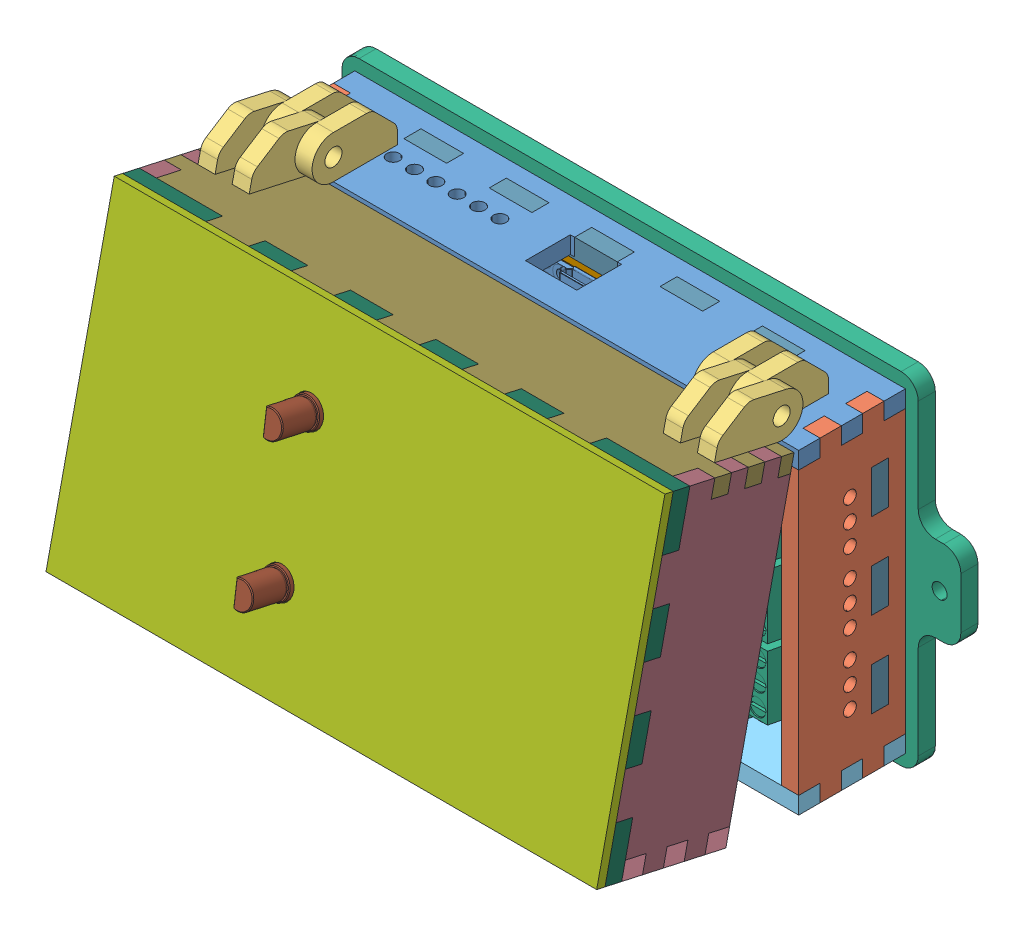
SolidWorks assembly KOOS, configuration Default. Lengths in mm.
Overall size (155 90.12 82.75).
54 component instances, 25 part files, 76 mates.
Components (placement in the parent):
- pcb^KOOS-1: pcb^KOOS [Default] at origin size (120 66.17 17.4) (virtual)
  - RaspberryPi_Pico_W^pcb_KOOS-1: RaspberryPi_Pico_W^pcb_KOOS [Default] at (102.465 -119.53 1.595) size (21 52.3 3.7) (virtual)
    - RaspberryPi_Pico_W_Module_KiCad^RaspberryPi_Pico_W_pcb_KOOS-1: RaspberryPi_Pico_W_Module_KiCad^RaspberryPi_Pico_W_pcb_KOOS [Default] at origin size (21 52.3 3.7) (virtual)
  - D_DO-41_SOD81_P10.16mm_Horizontal^pcb_KOOS-1: D_DO-41_SOD81_P10.16mm_Horizontal^pcb_KOOS [Default] at (136.74 -110.4 1.595) size (10.96 2.72 5.71) (virtual)
  - TerminalBlock_Phoenix_MKDS-1,5-2_1x02_P5.00mm_Horizontal^pcb_KOOS-1: TerminalBlock_Phoenix_MKDS-1,5-2_1x02_P5.00mm_Horizontal^pcb_KOOS [Default] at (49.6 -107.9 1.595) x (0 -1 0) z (0 0 1) size (10.74 9.8 17.3) (virtual)
  - R_Axial_DIN0207_L6.3mm_D2.5mm_P10.16mm_Horizontal^pcb_KOOS-1: R_Axial_DIN0207_L6.3mm_D2.5mm_P10.16mm_Horizontal^pcb_KOOS [Default] at (146.075 -143.595 1.595) x (0 1 0) z (0 0 1) size (10.76 2.5 5.5) (virtual)
  - DIP-4_W7.62mm^pcb_KOOS-1: DIP-4_W7.62mm^pcb_KOOS [Default] at (132.125 -128.705 1.595) x (0 1 0) z (0 0 1) size (7.87 4.93 6.98) (virtual)
  - TerminalBlock_Phoenix_MKDS-1,5-2_1x02_P5.00mm_Horizontal^pcb_KOOS-2: TerminalBlock_Phoenix_MKDS-1,5-2_1x02_P5.00mm_Horizontal^pcb_KOOS [Default] at (74.5 -151.5 1.595) size (10.74 9.8 17.3) (virtual)
  - TerminalBlock_Phoenix_MKDS-1,5-3_1x03_P5.00mm_Horizontal^pcb_KOOS-1: TerminalBlock_Phoenix_MKDS-1,5-3_1x03_P5.00mm_Horizontal^pcb_KOOS [Default] at (58 -151.5 1.595) size (15.74 9.8 17.3) (virtual)
  - R_Axial_DIN0207_L6.3mm_D2.5mm_P10.16mm_Horizontal^pcb_KOOS-2: R_Axial_DIN0207_L6.3mm_D2.5mm_P10.16mm_Horizontal^pcb_KOOS [Default] at (117.9 -123.32 1.595) x (0 -1 0) z (0 0 1) size (10.76 2.5 5.5) (virtual)
  - DIP-4_W7.62mm^pcb_KOOS-2: DIP-4_W7.62mm^pcb_KOOS [Default] at (138.4 -142.32 1.595) x (0 1 0) z (0 0 1) size (7.87 4.93 6.98) (virtual)
  - R_Axial_DIN0207_L6.3mm_D2.5mm_P10.16mm_Horizontal^pcb_KOOS-3: R_Axial_DIN0207_L6.3mm_D2.5mm_P10.16mm_Horizontal^pcb_KOOS [Default] at (76.675 -110.97 1.595) size (10.76 2.5 5.5) (virtual)
  - TerminalBlock_Phoenix_MKDS-1,5-3_1x03_P5.00mm_Horizontal^pcb_KOOS-2: TerminalBlock_Phoenix_MKDS-1,5-3_1x03_P5.00mm_Horizontal^pcb_KOOS [Default] at (49.6 -135.9 1.595) x (0 -1 0) z (0 0 1) size (15.74 9.8 17.3) (virtual)
  - R_Axial_DIN0207_L6.3mm_D2.5mm_P10.16mm_Horizontal^pcb_KOOS-4: R_Axial_DIN0207_L6.3mm_D2.5mm_P10.16mm_Horizontal^pcb_KOOS [Default] at (140.9 -119.82 1.595) x (0 -1 0) z (0 0 1) size (10.76 2.5 5.5) (virtual)
  - TerminalBlock_Phoenix_MKDS-1,5-2_1x02_P5.00mm_Horizontal^pcb_KOOS-3: TerminalBlock_Phoenix_MKDS-1,5-2_1x02_P5.00mm_Horizontal^pcb_KOOS [Default] at (144.4 -100.9 1.595) x (-1 0 0) z (0 0 1) size (10.74 9.8 17.3) (virtual)
  - R_Axial_DIN0207_L6.3mm_D2.5mm_P10.16mm_Horizontal^pcb_KOOS-5: R_Axial_DIN0207_L6.3mm_D2.5mm_P10.16mm_Horizontal^pcb_KOOS [Default] at (76.67 -115.045 1.595) size (10.76 2.5 5.5) (virtual)
  - TerminalBlock_Phoenix_MKDS-1,5-3_1x03_P5.00mm_Horizontal^pcb_KOOS-3: TerminalBlock_Phoenix_MKDS-1,5-3_1x03_P5.00mm_Horizontal^pcb_KOOS [Default] at (137.3 -151.5 1.595) size (15.74 9.8 17.3) (virtual)
  - LED_Rectangular_W5.0mm_H2.0mm^pcb_KOOS-1: LED_Rectangular_W5.0mm_H2.0mm^pcb_KOOS [Default] at (75.825 -123.92 1.595) x (0 1 0) z (0 0 1) size (5 2 15.1) (virtual)
  - TerminalBlock_Phoenix_MKDS-1,5-2_1x02_P5.00mm_Horizontal^pcb_KOOS-4: TerminalBlock_Phoenix_MKDS-1,5-2_1x02_P5.00mm_Horizontal^pcb_KOOS [Default] at (125.8 -151.5 1.595) size (10.74 9.8 17.3) (virtual)
  - TerminalBlock_Phoenix_MKDS-1,5-3_1x03_P5.00mm_Horizontal^pcb_KOOS-4: TerminalBlock_Phoenix_MKDS-1,5-3_1x03_P5.00mm_Horizontal^pcb_KOOS [Default] at (155.4 -131.4 1.595) x (0 1 0) z (0 0 1) size (15.74 9.8 17.3) (virtual)
  - R_Axial_DIN0207_L6.3mm_D2.5mm_P10.16mm_Horizontal^pcb_KOOS-6: R_Axial_DIN0207_L6.3mm_D2.5mm_P10.16mm_Horizontal^pcb_KOOS [Default] at (133.675 -133.435 1.595) x (0 -1 0) z (0 0 1) size (10.76 2.5 5.5) (virtual)
  - D_DO-41_SOD81_P10.16mm_Horizontal^pcb_KOOS-2: D_DO-41_SOD81_P10.16mm_Horizontal^pcb_KOOS [Default] at (136.74 -114.4 1.595) size (10.96 2.72 5.71) (virtual)
  - LED_Rectangular_W5.0mm_H2.0mm^pcb_KOOS-2: LED_Rectangular_W5.0mm_H2.0mm^pcb_KOOS [Default] at (81.2 -123.945 1.595) x (0 1 0) z (0 0 1) size (5 2 15.1) (virtual)
  - TerminalBlock_Phoenix_MKDS-1,5-3_1x03_P5.00mm_Horizontal^pcb_KOOS-5: TerminalBlock_Phoenix_MKDS-1,5-3_1x03_P5.00mm_Horizontal^pcb_KOOS [Default] at (49.6 -119.4 1.595) x (0 -1 0) z (0 0 1) size (15.74 9.8 17.3) (virtual)
  - TerminalBlock_Phoenix_PT-1,5-6-5.0-H_1x06_P5.00mm_Horizontal^pcb_KOOS-1: TerminalBlock_Phoenix_PT-1,5-6-5.0-H_1x06_P5.00mm_Horizontal^pcb_KOOS [Default] at (84.9 -100.9 1.595) x (-1 0 0) z (0 0 1) size (30.57 9 15) (virtual)
  - TerminalBlock_Phoenix_MKDS-1,5-3_1x03_P5.00mm_Horizontal^pcb_KOOS-6: TerminalBlock_Phoenix_MKDS-1,5-3_1x03_P5.00mm_Horizontal^pcb_KOOS [Default] at (155.4 -147.9 1.595) x (0 1 0) z (0 0 1) size (15.74 9.8 17.3) (virtual)
  - TerminalBlock_Phoenix_MKDS-1,5-3_1x03_P5.00mm_Horizontal^pcb_KOOS-7: TerminalBlock_Phoenix_MKDS-1,5-3_1x03_P5.00mm_Horizontal^pcb_KOOS [Default] at (155.4 -114.9 1.595) x (0 1 0) z (0 0 1) size (15.74 9.8 17.3) (virtual)
  - pcb_PCB^pcb_KOOS-1: pcb_PCB^pcb_KOOS [Default] at origin size (120 65 1.51) (virtual)
- OLED_IIC_096^KOOS-1: OLED_IIC_096^KOOS [Default] at (134.2 -123.2207 53.1382) x (-1 0 0) z (0 -0.215995 -0.976394) size (27.6 27.2 11) (virtual)
- Rotary-Encoder^KOOS-1: Rotary-Encoder^KOOS [Default] at (72.8 -112.0538 34.5883) x (1 0 0) z (0 0.215995 0.976394) size (27.6 18.4 29.2) (virtual)
- Rotary-Encoder^KOOS-2: Rotary-Encoder^KOOS [Default] at (72.8 -143.2984 41.5001) x (1 0 0) z (0 0.215995 0.976394) size (27.6 18.4 29.2) (virtual)
- külg_pikem_1-2: külg_pikem_1 [Default] at (41.9 -83.8821 42.4898) x (1 0 0) z (0 -0.215995 -0.976394) size (129 4 29)
- külg_lühem_1-1: külg_lühem_1 [Default] at (37.9 -152.2297 57.6095) x (0 0.976394 -0.215995) z (0 -0.215995 -0.976394) size (74 4 29)
- külg_lühem_1-2: külg_lühem_1 [Default] at (162.9 -152.2297 57.6095) x (0 0.976394 -0.215995) z (0 -0.215995 -0.976394) size (74 4 29)
- raam_1-1: raam_1 [Default] at (41.9 -93.4 -4) x (1 0 0) z (0 -1 0) size (129 4 74)
- peamine_1-1: peamine_1 [Default] at (37.9 -83.8821 42.4898) x (1 0 0) z (0 -0.976394 0.215995) size (129 4 74)
- peamine_2-1: peamine_2 [Default] at (41.9 -152.2297 57.6095) x (1 0 0) z (0 0.976394 -0.215995) size (121 4 66)
- ekraani_kinnitus_1-1: ekraani_kinnitus_1 [Default] at (131.15 -89.5156 35.5427) x (0 -0.976394 0.215995) z (-1 0 0) size (66 4 20)
- rotary_kinnitus_1-1: rotary_kinnitus_1 [Default] at (97.7 -89.9044 33.7852) x (0 -0.976394 0.215995) z (-1 0 0) size (66 4 20)
- pcb_külg_pikem_1-1: pcb_külg_pikem_1 [USB_poolne] at (41.9 -93.4 -8) size (129 4 29)
- pcb_külg_lühem_1-1: pcb_külg_lühem_1 [Default] at (166.9 -159.4 -8) x (0 1 0) z (0 0 1) size (74 4 29)
- pcb_külg_lühem_1-2: pcb_külg_lühem_1 [teine] at (41.9 -159.4 -8) x (0 1 0) z (0 0 1) size (74 4 29)
- hing_1-4: hing_1 [Default] at (41.9 -84.4 17) x (0 0.976394 -0.215995) z (0 -0.215995 -0.976394) size (14 4 20)
- hing_1-7: hing_1 [Default] at (49.9 -84.4 17) x (0 0.976394 -0.215995) z (0 -0.215995 -0.976394) size (14 4 20)
- hing_1-8: hing_1 [Default] at (158.9 -84.4 17) x (0 0.976394 -0.215995) z (0 -0.215995 -0.976394) size (14 4 20)
- hing_1-9: hing_1 [Default] at (150.9 -84.4 17) x (0 0.976394 -0.215995) z (0 -0.215995 -0.976394) size (14 4 20)
- hing_1-10: hing_1 [Default] at (158.9 -84.4 17) x (0 1 0) z (0 0 1) size (14 4 20)
- hing_1-11: hing_1 [Default] at (150.9 -84.4 17) x (0 1 0) z (0 0 1) size (14 4 20)
- hing_1-12: hing_1 [Default] at (49.9 -84.4 17) x (0 1 0) z (0 0 1) size (14 4 20)
- hing_1-13: hing_1 [Default] at (57.9 -84.4 17) x (0 1 0) z (0 0 1) size (14 4 20)
- külg_pikem_2-1: külg_pikem_2 [Default] at (41.9 -152.2297 57.6095) x (1 0 0) z (0 -0.215995 -0.976394) size (129 4 29)
- pcb_külg_pikem_2-1: pcb_külg_pikem_2 [Default] at (41.9 -163.4 -8) size (129 4 29)
- kinnitus_plaat-1: kinnitus_plaat [Default] at (37.9 -89.4 -12) x (1 0 0) z (0 -1 0) size (155 4 80)
- pleksiklaas_1-1: pleksiklaas_1 [Default] at (166.9 -82.5861 48.3482) x (-1 0 0) z (0 -0.976394 0.215995) size (129 2 74)
Mates (geometry in assembly coordinates):
- Coincident1: coincident aligned: plane of Rotary-Encoder^KOOS-1 through (84.9 -104.4252 42.2207) normal (0 0.215995 0.976394); plane of Rotary-Encoder^KOOS-2 through (84.9 -135.6698 49.1325) normal (0 0.215995 0.976394)
- Coincident2: coincident aligned: plane of Rotary-Encoder^KOOS-1 through (71.1 -104.4252 42.2207) normal (-1 0 0); plane of Rotary-Encoder^KOOS-2 through (71.1 -135.6698 49.1325) normal (-1 0 0)
- Coincident8: coincident aligned: plane of külg_pikem_1-2 through (41.9 -87.7877 43.3538) normal (0 0.215995 0.976394); plane of külg_lühem_1-1 through (41.9 -152.2297 57.6095) normal (0 0.215995 0.976394)
- Coincident11: coincident aligned: plane of külg_lühem_1-1 through (41.9 -152.2297 57.6095) normal (0 0.215995 0.976394); plane of külg_lühem_1-2 through (166.9 -152.2297 57.6095) normal (0 0.215995 0.976394)
- Coincident17: coincident anti-aligned: plane of külg_pikem_1-2 through (41.9 -87.7877 43.3538) normal (0 0.215995 0.976394); plane of peamine_1-1 through (37.9 -83.8821 42.4898) normal (0 -0.215995 -0.976394)
- Coincident18: coincident aligned: plane of külg_pikem_1-2 through (41.9 -83.8821 42.4898) normal (0 0.976394 -0.215995); plane of peamine_1-1 through (37.9 -83.0181 46.3954) normal (0 0.976394 -0.215995)
- Coincident19: coincident aligned: plane of külg_lühem_1-1 through (37.9 -152.2297 57.6095) normal (-1 0 0); plane of peamine_1-1 through (37.9 -83.0181 46.3954) normal (-1 0 0)
- Coincident20: coincident anti-aligned: plane of Rotary-Encoder^KOOS-2 through (84.9 -134.6546 53.7216) normal (0 0.215995 0.976394); plane of peamine_1-1 through (37.9 -83.8821 42.4898) normal (0 -0.215995 -0.976394)
- Concentric1: concentric anti-aligned: cylinder of Rotary-Encoder^KOOS-2 through (87.9 -134.119 60.7723) axis (0 -0.215995 -0.976394) radius 3.35; cylinder of peamine_1-1 through (87.9 -135.631 53.9376) axis (0 0.215995 0.976394) radius 3.5
- Concentric2: concentric anti-aligned: cylinder of Rotary-Encoder^KOOS-1 through (87.9 -102.8744 53.8605) axis (0 -0.215995 -0.976394) radius 3.35; cylinder of peamine_1-1 through (87.9 -104.3864 47.0257) axis (0 0.215995 0.976394) radius 3.5
- Coincident21: coincident anti-aligned: plane of OLED_IIC_096^KOOS-1 through (121.4 -106.4386 49.3232) normal (0 0.976394 -0.215995); plane of peamine_1-1 through (111.9 -106.8274 47.5657) normal (0 -0.976394 0.215995)
- Coincident22: coincident anti-aligned: plane of OLED_IIC_096^KOOS-1 through (130.9 -119.5223 52.2176) normal (1 0 0); plane of peamine_1-1 through (130.9 -106.8274 47.5657) normal (-1 0 0)
- Coincident23: coincident anti-aligned: plane of OLED_IIC_096^KOOS-1 through (122.1 -119.911 50.4601) normal (0 0.215995 0.976394); plane of peamine_1-1 through (37.9 -83.8821 42.4898) normal (0 -0.215995 -0.976394)
- Coincident24: coincident anti-aligned: plane of peamine_1-1 through (37.9 -83.8821 42.4898) normal (0 -0.215995 -0.976394); plane of peamine_2-1 through (41.9 -152.2297 57.6095) normal (0 0.215995 0.976394)
- Coincident25: coincident anti-aligned: plane of külg_pikem_1-2 through (41.9 -87.7877 43.3538) normal (0 -0.976394 0.215995); plane of peamine_2-1 through (41.9 -88.6517 39.4482) normal (0 0.976394 -0.215995)
- Coincident26: coincident anti-aligned: plane of külg_lühem_1-2 through (162.9 -152.2297 57.6095) normal (-1 0 0); plane of peamine_2-1 through (162.9 -153.0937 53.7039) normal (1 0 0)
- Coincident27: coincident anti-aligned: plane of peamine_2-1 through (41.9 -153.0937 53.7039) normal (0 -0.215995 -0.976394); plane of ekraani_kinnitus_1-1 through (131.15 -88.6517 39.4482) normal (0 0.215995 0.976394)
- Coincident28: coincident anti-aligned: plane of külg_pikem_1-2 through (41.9 -87.7877 43.3538) normal (0 -0.976394 0.215995); plane of ekraani_kinnitus_1-1 through (131.15 -88.6517 39.4482) normal (0 0.976394 -0.215995)
- Distance4: distance = 5 mm anti-aligned: plane of peamine_2-1 through (136.15 -133.6782 53.5056) normal (-1 0 0); plane of ekraani_kinnitus_1-1 through (131.15 -88.6517 39.4482) normal (1 0 0)
- Coincident30: coincident anti-aligned: plane of Rotary-Encoder^KOOS-2 through (84.9 -135.9074 48.0585) normal (0 -0.215995 -0.976394); plane of rotary_kinnitus_1-1 through (97.7 -89.0404 37.6907) normal (0 0.215995 0.976394)
- Coincident31: coincident anti-aligned: plane of külg_pikem_1-2 through (41.9 -87.7877 43.3538) normal (0 -0.976394 0.215995); plane of rotary_kinnitus_1-1 through (97.7 -89.0404 37.6907) normal (0 0.976394 -0.215995)
- Distance5: distance = 1 mm aligned: plane of Rotary-Encoder^KOOS-1 through (98.7 -104.4252 42.2207) normal (1 0 0); plane of rotary_kinnitus_1-1 through (97.7 -89.0404 37.6907) normal (1 0 0)
- Coincident32: coincident anti-aligned: plane of raam_1-1 through (41.9 -93.4 0) normal (0 1 0); plane of pcb_külg_pikem_1-1 through (41.9 -93.4 -8) normal (0 -1 0)
- Coincident33: coincident anti-aligned: plane of raam_1-1 through (147.4 -89.4 -4) normal (1 0 0); plane of pcb_külg_pikem_1-1 through (147.4 -89.4 0) normal (-1 0 0)
- Coincident34: coincident anti-aligned: plane of raam_1-1 through (41.9 -93.4 0) normal (0 0 1); plane of pcb_külg_pikem_1-1 through (137.4 -89.4 0) normal (0 0 -1)
- Coincident38: coincident anti-aligned: plane of pcb_külg_pikem_1-1 through (162.9 -89.4 -8) normal (1 0 0); plane of pcb_külg_lühem_1-1 through (162.9 -159.4 -8) normal (-1 0 0)
- Coincident39: coincident aligned: plane of pcb_külg_pikem_1-1 through (41.9 -89.4 17) normal (0 0 1); plane of pcb_külg_lühem_1-1 through (162.9 -159.4 17) normal (0 0 1)
- Coincident41: coincident anti-aligned: plane of pcb_külg_pikem_1-1 through (41.9 -93.4 -8) normal (0 -1 0); plane of pcb_külg_lühem_1-1 through (162.9 -93.4 -8) normal (0 1 0)
- Coincident42: coincident aligned: plane of pcb_külg_pikem_1-1 through (37.9 -89.4 -3) normal (-1 0 0); plane of pcb_külg_lühem_1-2 through (37.9 -159.4 -8) normal (-1 0 0)
- Coincident43: coincident aligned: plane of pcb_külg_pikem_1-1 through (41.9 -89.4 17) normal (0 0 1); plane of pcb_külg_lühem_1-2 through (37.9 -159.4 17) normal (0 0 1)
- Coincident45: coincident aligned: plane of pcb_külg_pikem_1-1 through (41.9 -89.4 -8) normal (0 1 0); plane of pcb_külg_lühem_1-2 through (41.9 -89.4 7) normal (0 1 0)
- Distance7: distance = 0.5 mm anti-aligned: plane of pcb^KOOS-1/pcb_PCB^pcb_KOOS-1 through (42.4 -154.9 0) normal (-1 0 0); plane of pcb_külg_lühem_1-2 through (41.9 -159.4 -8) normal (1 0 0)
- Coincident50: coincident aligned: plane of külg_lühem_1-1 through (37.9 -152.2297 57.6095) normal (-1 0 0); plane of pcb_külg_lühem_1-2 through (37.9 -159.4 -8) normal (-1 0 0)
- Coincident51: coincident anti-aligned: plane of pcb^KOOS-1/pcb_PCB^pcb_KOOS-1 through (0 0 0) normal (0 0 -1); plane of raam_1-1 through (41.9 -93.4 0) normal (0 0 1)
- Coincident75: coincident anti-aligned: plane of külg_pikem_1-2 through (41.9 -83.8821 42.4898) normal (0 0.976394 -0.215995); plane of hing_1-4 through (45.9 -89.282 18.08) normal (0 -0.976394 0.215995)
- Distance14: distance = 3 mm aligned: plane of hing_1-4 through (45.9 -83.752 19.9292) normal (0 -0.215995 -0.976394); plane of külg_pikem_1-2 through (41.9 -93.1875 18.944) normal (0 -0.215995 -0.976394)
- Distance15: distance = 4 mm aligned: plane of hing_1-4 through (41.9 -84.4 17) normal (-1 0 0); plane of külg_lühem_1-1 through (37.9 -152.2297 57.6095) normal (-1 0 0)
- Coincident78: coincident aligned: plane of hing_1-4 through (45.9 -79.518 15.92) normal (0 0.976394 -0.215995); plane of hing_1-7 through (53.9 -79.518 15.92) normal (0 0.976394 -0.215995)
- Coincident79: coincident aligned: plane of hing_1-4 through (45.9 -81.1601 31.6459) normal (0 0.215995 0.976394); plane of hing_1-7 through (53.9 -81.1601 31.6459) normal (0 0.215995 0.976394)
- Distance16: distance = 4 mm anti-aligned: plane of hing_1-7 through (49.9 -84.4 17) normal (-1 0 0); plane of hing_1-4 through (45.9 -84.4 17) normal (1 0 0)
- Coincident81: coincident aligned: plane of hing_1-7 through (53.9 -79.518 15.92) normal (0 0.976394 -0.215995); plane of hing_1-8 through (162.9 -79.518 15.92) normal (0 0.976394 -0.215995)
- Distance17: distance = 4 mm aligned: plane of hing_1-8 through (162.9 -84.4 17) normal (1 0 0); plane of külg_lühem_1-2 through (166.9 -152.2297 57.6095) normal (1 0 0)
- Coincident83: coincident aligned: plane of hing_1-7 through (53.9 -81.1601 31.6459) normal (0 0.215995 0.976394); plane of hing_1-8 through (162.9 -81.1601 31.6459) normal (0 0.215995 0.976394)
- Coincident84: coincident aligned: plane of hing_1-8 through (162.9 -81.1601 31.6459) normal (0 0.215995 0.976394); plane of hing_1-9 through (154.9 -81.1601 31.6459) normal (0 0.215995 0.976394)
- Coincident85: coincident aligned: plane of hing_1-8 through (162.9 -79.518 15.92) normal (0 0.976394 -0.215995); plane of hing_1-9 through (154.9 -79.518 15.92) normal (0 0.976394 -0.215995)
- Distance18: distance = 4 mm anti-aligned: plane of hing_1-8 through (158.9 -84.4 17) normal (-1 0 0); plane of hing_1-9 through (154.9 -84.4 17) normal (1 0 0)
- Distance19: distance = 3 mm aligned: plane of pcb_külg_pikem_1-1 through (41.9 -89.4 17) normal (0 0 1); plane of hing_1-10 through (154.9 -84.4 14) normal (0 0 1)
- Coincident88: coincident anti-aligned: plane of pcb_külg_pikem_1-1 through (41.9 -89.4 -8) normal (0 1 0); plane of hing_1-10 through (154.9 -89.4 17) normal (0 -1 0)
- Distance20: distance = 8 mm aligned: plane of pcb_külg_lühem_1-1 through (166.9 -159.4 -8) normal (1 0 0); plane of hing_1-10 through (158.9 -84.4 17) normal (1 0 0)
- Coincident90: coincident aligned: plane of hing_1-10 through (154.9 -79.4 17) normal (0 1 0); plane of hing_1-11 through (146.9 -79.4 17) normal (0 1 0)
- Coincident91: coincident aligned: plane of hing_1-10 through (154.9 -84.4 2) normal (0 0 -1); plane of hing_1-11 through (146.9 -84.4 2) normal (0 0 -1)
- Distance21: distance = 4 mm anti-aligned: plane of hing_1-11 through (150.9 -84.4 17) normal (1 0 0); plane of hing_1-10 through (154.9 -84.4 17) normal (-1 0 0)
- Concentric5: concentric anti-aligned: cylinder of hing_1-9 through (154.9 -84.4 17) axis (-1 0 0) radius 2; cylinder of hing_1-11 through (146.9 -84.4 17) axis (1 0 0) radius 2
- Coincident92: coincident aligned: plane of hing_1-11 through (146.9 -79.4 17) normal (0 1 0); plane of hing_1-12 through (45.9 -79.4 17) normal (0 1 0)
- Coincident93: coincident aligned: plane of hing_1-11 through (146.9 -84.4 2) normal (0 0 -1); plane of hing_1-12 through (45.9 -84.4 2) normal (0 0 -1)
- Distance22: distance = 8 mm aligned: plane of hing_1-12 through (45.9 -84.4 17) normal (-1 0 0); plane of pcb_külg_lühem_1-2 through (37.9 -159.4 -8) normal (-1 0 0)
- Coincident95: coincident aligned: plane of hing_1-12 through (45.9 -79.4 17) normal (0 1 0); plane of hing_1-13 through (53.9 -79.4 17) normal (0 1 0)
- Coincident96: coincident aligned: plane of hing_1-12 through (45.9 -84.4 2) normal (0 0 -1); plane of hing_1-13 through (53.9 -84.4 2) normal (0 0 -1)
- Coincident97: coincident anti-aligned: plane of hing_1-7 through (53.9 -84.4 17) normal (1 0 0); plane of hing_1-13 through (53.9 -84.4 17) normal (-1 0 0)
- Coincident98: coincident aligned: plane of peamine_1-1 through (37.9 -155.2713 62.3791) normal (0 -0.976394 0.215995); plane of külg_pikem_2-1 through (41.9 -156.1353 58.4735) normal (0 -0.976394 0.215995)
- Coincident99: coincident aligned: plane of peamine_1-1 through (37.9 -83.0181 46.3954) normal (0 0.215995 0.976394); plane of külg_pikem_2-1 through (137.4 -155.2713 62.3791) normal (0 0.215995 0.976394)
- Coincident100: coincident aligned: plane of külg_lühem_1-2 through (166.9 -152.2297 57.6095) normal (1 0 0); plane of külg_pikem_2-1 through (166.9 -153.3097 52.7275) normal (1 0 0)
- Coincident101: coincident aligned: plane of pcb_külg_lühem_1-1 through (166.9 -163.4 7) normal (0 -1 0); plane of pcb_külg_pikem_2-1 through (41.9 -163.4 -8) normal (0 -1 0)
- Coincident102: coincident aligned: plane of pcb_külg_lühem_1-1 through (166.9 -159.4 -8) normal (1 0 0); plane of pcb_külg_pikem_2-1 through (166.9 -159.4 17) normal (1 0 0)
- Coincident103: coincident aligned: plane of pcb_külg_lühem_1-1 through (166.9 -151.4 -12) normal (0 0 -1); plane of pcb_külg_pikem_2-1 through (137.4 -159.4 -12) normal (0 0 -1)
- Distance23: distance = 0.5 mm anti-aligned: plane of pcb^KOOS-1/pcb_PCB^pcb_KOOS-1 through (158.4 -158.9 0) normal (0 -1 0); plane of pcb_külg_pikem_2-1 through (41.9 -159.4 -8) normal (0 1 0)
- Coincident105: coincident aligned: plane of külg_lühem_1-2 through (166.9 -152.2297 57.6095) normal (1 0 0); plane of peamine_1-1 through (166.9 -83.0181 46.3954) normal (1 0 0)
- Coincident106: coincident aligned: plane of külg_lühem_1-2 through (162.9 -157.2153 53.5915) normal (0 -0.976394 0.215995); plane of külg_pikem_2-1 through (41.9 -156.1353 58.4735) normal (0 -0.976394 0.215995)
- Coincident107: coincident aligned: plane of külg_lühem_1-1 through (37.9 -157.2153 53.5915) normal (0 -0.976394 0.215995); plane of külg_pikem_2-1 through (41.9 -156.1353 58.4735) normal (0 -0.976394 0.215995)
- Coincident108: coincident aligned: plane of külg_pikem_1-2 through (37.9 -86.042 32.7259) normal (-1 0 0); plane of külg_lühem_1-1 through (37.9 -152.2297 57.6095) normal (-1 0 0)
- Coincident109: coincident anti-aligned: plane of pcb_külg_lühem_1-1 through (162.9 -159.4 -8) normal (0 0 -1); plane of kinnitus_plaat-1 through (37.9 -89.4 -8) normal (0 0 1)
- Coincident113: coincident anti-aligned: plane of pcb_külg_lühem_1-1 through (166.9 -159.4 -8) normal (1 0 0); plane of kinnitus_plaat-1 through (166.9 -89.4 -12) normal (-1 0 0)
- Coincident114: coincident anti-aligned: plane of pcb_külg_pikem_1-1 through (41.9 -89.4 -8) normal (0 1 0); plane of kinnitus_plaat-1 through (37.9 -89.4 -12) normal (0 -1 0)
- Coincident115: coincident anti-aligned: plane of peamine_1-1 through (37.9 -83.0181 46.3954) normal (0 0.215995 0.976394); plane of pleksiklaas_1-1 through (166.9 -83.0181 46.3954) normal (0 -0.215995 -0.976394)
- Coincident116: coincident aligned: plane of külg_pikem_1-2 through (41.9 -83.8821 42.4898) normal (0 0.976394 -0.215995); plane of pleksiklaas_1-1 through (166.9 -83.0181 46.3954) normal (0 0.976394 -0.215995)
- Coincident117: coincident aligned: plane of külg_lühem_1-2 through (166.9 -152.2297 57.6095) normal (1 0 0); plane of pleksiklaas_1-1 through (166.9 -83.0181 46.3954) normal (1 0 0)
